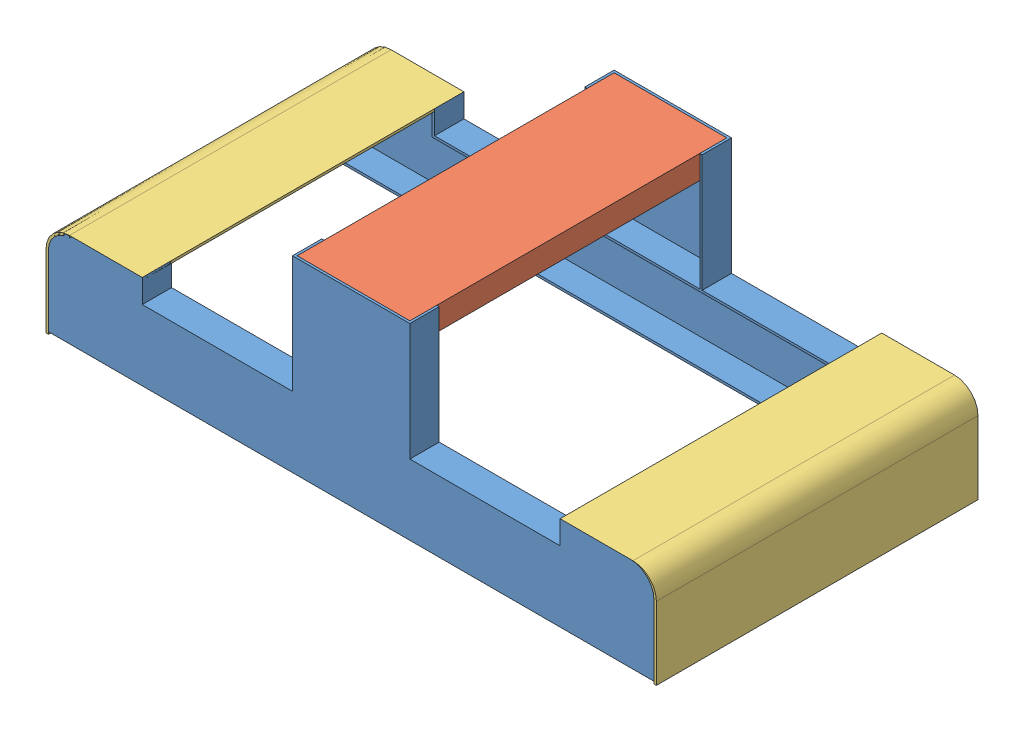
SolidWorks assembly Assem1, configuration Default. Lengths in mm.
Overall size (520 162 274).
5 component instances, 3 part files, 19 mates.
Components (placement in the parent):
- Part8-1: Part8 [Default] at (-296.7289 -84.4445 22.3685) size (516 160 25)
- Part8-2: Part8 [Default] at (219.2711 -84.4445 -251.6315) x (-1 0 0) z (0 0 -1) size (516 160 25)
- Part6-2: Part6 [Default] at (-86.7289 75.5555 -249.6315) x (1 0 0) z (0 0 -1) size (96 20 270)
- Part3-1: Part3 [Default] at (-296.7289 -86.4445 22.3685) size (82 82 274)
- Part3-2: Part3 [Default] at (219.2711 -86.4445 -251.6315) x (-1 0 0) z (0 0 -1) size (82 82 274)
Mates (geometry in assembly coordinates):
- Parallel2: parallel: plane of Part8-1 through (-276.7289 -24.4445 20.3685) normal (0 0 -1); plane of Part8-2 through (199.2711 -24.4445 -249.6315) normal (0 0 1)
- Coincident11: coincident: plane of Part8-2 through (9.2711 -123.1613 -249.6315) normal (0 0 1); plane of Part6-2 through (-86.7289 75.5555 -249.6315) normal (0 0 -1)
- Coincident12: coincident: plane of Part8-1 through (-86.7289 -123.1613 20.3685) normal (0 0 -1); plane of Part6-2 through (-86.7289 75.5555 20.3685) normal (0 0 1)
- Coincident13: coincident: plane of Part8-2 through (-86.7289 -123.1613 -249.6315) normal (1 0 0); plane of Part6-2 through (-86.7289 75.5555 20.3685) normal (-1 0 0)
- Coincident14: coincident: plane of Part8-1 through (-86.7289 -123.1613 -2.6315) normal (1 0 0); plane of Part6-2 through (-86.7289 75.5555 20.3685) normal (-1 0 0)
- Coincident15: coincident: plane of Part8-2 through (11.2711 75.5555 -226.6315) normal (0 1 0); plane of Part6-2 through (-86.7289 75.5555 20.3685) normal (0 1 0)
- Coincident17: coincident: plane of Part8-1 through (-276.7289 -24.4445 -2.6315) normal (0 0 -1); plane of Part3-1 through (-278.7289 -24.4445 -2.6315) normal (0 0 1)
- Parallel3: parallel: plane of Part8-2 through (-216.7289 -24.4445 -226.6315) normal (0 1 0); plane of Part3-1 through (-278.7289 -4.4445 -251.6315) normal (0 1 0)
- Parallel4: parallel: plane of Part8-2 through (-296.7289 -84.4445 -226.6315) normal (-1 0 0); plane of Part3-1 through (-298.7289 -86.4445 -251.6315) normal (-1 0 0)
- Coincident20: coincident: plane of Part8-1 through (-88.7289 75.5555 -2.6315) normal (0 1 0); plane of Part6-2 through (-86.7289 75.5555 20.3685) normal (0 1 0)
- Coincident23: coincident: line of Part8-1 through (-216.7289 -24.4445 -2.6315) axis (0 1 0); line of Part3-1 through (-216.7289 -6.4445 -2.6315) axis (0 1 0)
- Coincident24: coincident: line of Part8-1 through (-216.7289 -4.4445 -2.6315) axis (0 0 1); line of Part3-1 through (-216.7289 -4.4445 -251.6315) axis (0 0 1)
- Coincident26: coincident: line of Part8-1 through (199.2711 -4.4445 -2.6315) axis (-1 0 0); line of Part3-2 through (139.2711 -4.4445 -2.6315) axis (1 0 0)
- Coincident27: coincident: point of Part8-1; point of Part3-2
- Coincident29: coincident: point of Part8-1; point of Part3-2
- Parallel6: parallel: plane of Part8-1 through (199.2711 -4.4445 -2.6315) normal (0 1 0); plane of Part3-2 through (201.2711 -4.4445 22.3685) normal (0 1 0)
- Coincident33: coincident: line of Part8-1 through (199.2711 -4.4445 22.3685) axis (-1 0 0); line of Part3-2 through (139.2711 -4.4445 22.3685) axis (1 0 0)
- Coincident34: coincident: line of Part8-1 through (139.2711 -4.4445 22.3685) axis (0 -1 0); line of Part3-2 through (139.2711 -6.4445 22.3685) axis (0 1 0)
- Coincident36: coincident: line of Part8-1 through (-216.7289 -4.4445 22.3685) axis (-1 0 0); line of Part3-1 through (-216.7289 -4.4445 22.3685) axis (-1 0 0)
